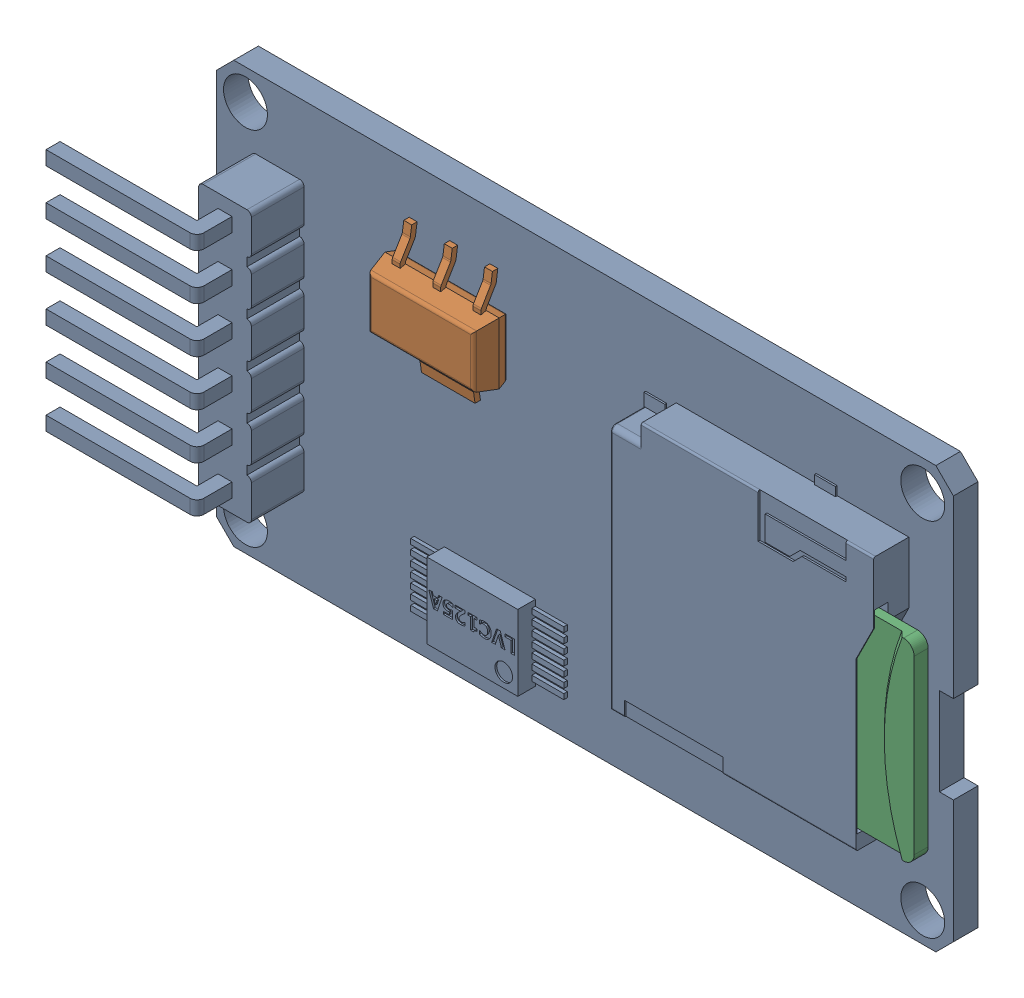
SolidWorks assembly SD, configuration Default. Lengths in mm.
Overall size (46.9 24 6.7).
5 component instances, 3 part files, 0 mates.
Components (placement in the parent):
- MicroSD_Reader_Assembly-1: MicroSD_Reader_Assembly [Default] at (210.8201 82.6769 0.127) x (-1 0 0) z (0 0 1) size (46.9 24 6.7)
  - sdreader-1: sdreader [Default] at (-11.2744 2.632 -3.2) size (46.9 24 6.7)
    - Open CASCADE STEP translator 6.8 2.9.1.1.1-1: Open CASCADE STEP translator 6.8 2.9.1.1.1 [Default] at origin size (46.9 24 6.7)
  - AMS1117-1: AMS1117 [Default] at (-0.4339 -2.128 -1.13) x (1 0 0) z (0 -1 0) size (6.51 1.86 7)
  - card_sd-1: card_sd [Default] at (-21.187 5.4466 -0.36) x (0 -1 0) z (0 0 1) size (11 15 0.82)
